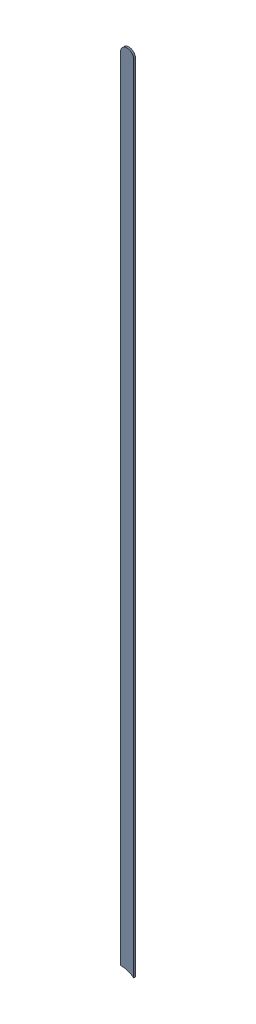
SolidWorks assembly Track (19.202mm,28.302mm)(19.202mm,43.865mm) on Bottom Layer, configuration Predeterminado. Lengths in mm.
Overall size (0.25 15.52 0.04).
2 component instances, 1 part files, 0 mates.
Components (placement in the parent):
- Track (19.202mm,28.302mm)(19.202mm,43.865mm) on Bottom Layer-1-1: Track (19.202mm,28.302mm)(19.202mm,43.865mm) on Bottom Layer-1 [Predeterminado] at (-68.317 -44.187 -0.4013) size (0.25 15.52 0.04)
  - Track (19.202mm,28.302mm)(19.202mm,43.865mm) on Bottom Layer-Part-1-1: Track (19.202mm,28.302mm)(19.202mm,43.865mm) on Bottom Layer-Part-1 [Predeterminado] at origin size (0.25 15.52 0.04)
